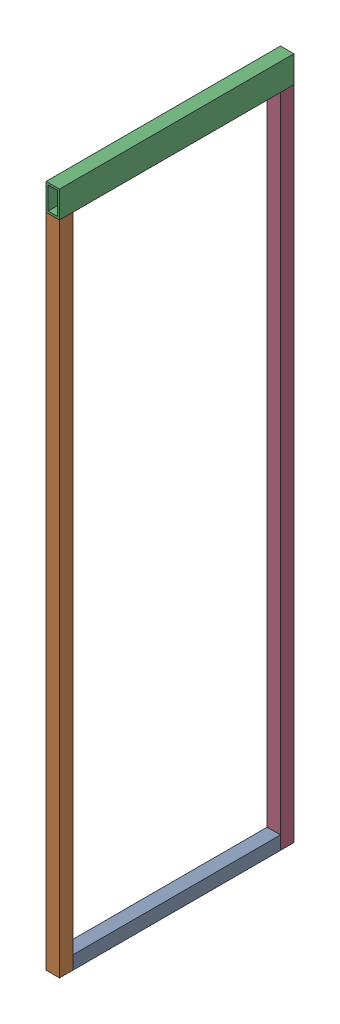
SolidWorks assembly 010112_frame_motor_side, configuration Default. Lengths in mm.
Overall size (40 2040 700).
4 component instances, 3 part files, 6 mates.
Components (placement in the parent):
- 010101_ST_40x4x620-1: 010101_ST_40x4x620 [Default] at (490.7101 534.345 197.13) size (40 40 620)
- 010102_ST_40x4x1960-1: 010102_ST_40x4x1960 [Default] at (490.7101 514.345 837.13) x (1 0 0) z (0 1 0) size (40 40 1960)
- 010111_RT_80x40x6.3x700-1: 010111_RT_80x40x6.3x700 [Default] at (490.7101 2514.345 507.13) size (40 80 700)
- 010102_ST_40x4x1960-2: 010102_ST_40x4x1960 [Default] at (490.7101 2474.345 177.13) x (1 0 0) z (0 -1 0) size (40 40 1960)
Mates (geometry in assembly coordinates):
- Coincident1: coincident aligned: plane of 010102_ST_40x4x2140-1 through (490.7101 514.345 837.13) normal (0 -1 0); plane of 010101_ST_40x4x1000-1 through (470.7101 514.345 197.13) normal (0 -1 0)
- Coincident2: coincident anti-aligned: plane of 010101_ST_40x4x1000-1 through (490.7101 534.345 817.13) normal (0 0 1); plane of 010102_ST_40x4x2140-1 through (470.7101 514.345 817.13) normal (0 0 -1)
- Coincident3: coincident aligned: plane of 010101_ST_40x4x1000-1 through (510.7101 554.345 197.13) normal (1 0 0); plane of 010102_ST_40x4x2140-1 through (510.7101 514.345 817.13) normal (1 0 0)
- Coincident4: coincident aligned: plane of 010102_ST_40x4x2140-1 through (470.7101 514.345 857.13) normal (0 0 1); plane of 010111_RT_80x40x6.3x1080-1 through (490.7101 2514.345 857.13) normal (0 0 1)
- Coincident5: coincident aligned: plane of 010102_ST_40x4x2140-1 through (510.7101 514.345 817.13) normal (1 0 0); plane of 010111_RT_80x40x6.3x1080-1 through (510.7101 2554.345 857.13) normal (1 0 0)
- Coincident6: coincident anti-aligned: plane of 010102_ST_40x4x2140-1 through (490.7101 2474.345 837.13) normal (0 1 0); plane of 010111_RT_80x40x6.3x1080-1 through (470.7101 2474.345 857.13) normal (0 -1 0)
